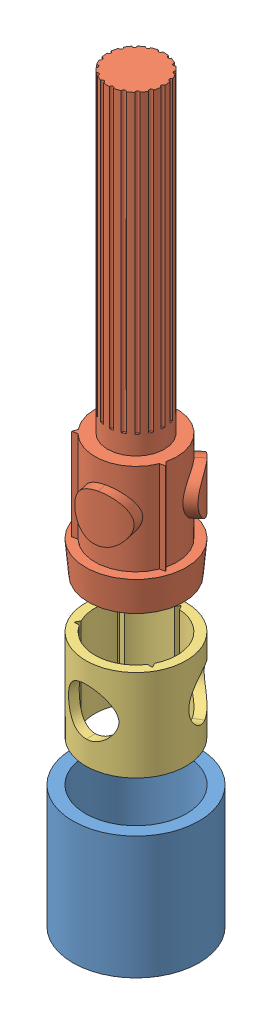
SolidWorks assembly MoldAssmably02, configuration Standard. Lengths in mm.
Overall size (43.02 235.7 43.02).
3 component instances, 3 part files, 2 mates.
Components (placement in the parent):
- 3WayValve_RIng_MoldPartA-1: 3WayValve_RIng_MoldPartA [Standard] at (-44.3863 -20.129 40) size (40 39 40)
- 3WayValve_RIng_MoldPartB-1: 3WayValve_RIng_MoldPartB [Standard] at (-44.3863 76.5735 40) x (0.889117 0 -0.45768) z (0.45768 0 0.889117) size (31.95 139 31.95)
- TPERing_V1_0_3_MoldV_SAK-1: TPERing_V1_0_3_MoldV_SAK [Standard] at (-44.3863 31.9493 40) size (31.85 29 31.85)
Mates (geometry in assembly coordinates):
- Konzentrisch1: concentric aligned: cylinder of 3WayValve_RIng_MoldPartA-1 through (-44.3863 18.871 40) axis (0 -1 0) radius 20; cylinder of 3WayValve_RIng_MoldPartB-1 through (-44.3863 115.6605 40) axis (0 -1 0) radius 13.039
- Konzentrisch2: concentric aligned: cylinder of 3WayValve_RIng_MoldPartB-1 through (-44.3863 115.6605 40) axis (0 -1 0) radius 13.039; cylinder of TPERing_V1_0_3_MoldV_SAK-1 through (-44.3863 60.9493 40) axis (0 -1 0) radius 15.925
